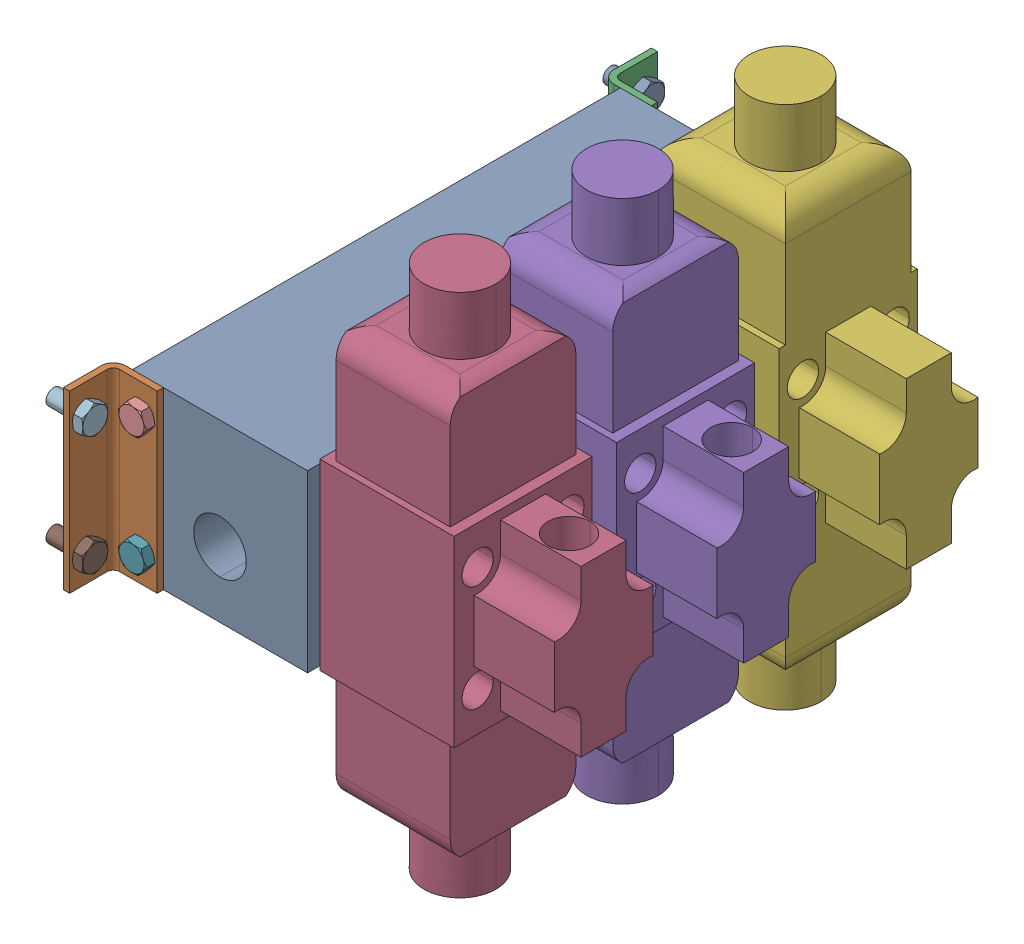
SolidWorks assembly 01-119-00-0, configuration Default. Lengths in mm.
Overall size (220.24 266.21 298.46).
14 component instances, 5 part files, 0 mates.
Components (placement in the parent):
- DAMAN-AD05S033S VALVE BLOCK-1: DAMAN-AD05S033S VALVE BLOCK [Default] at origin size (88.92 88.92 247.67)
- DAMANAD05S033S MOUNTING BRACKET-1: DAMANAD05S033S MOUNTING BRACKET [Default] at origin size (25.42 88.91 25.42)
- DAMANAD05S033S MOUNTING BRACKET-2: DAMANAD05S033S MOUNTING BRACKET [Default] at (0 88.9 -247.65) x (1 0 0) z (0 0 -1) size (25.42 88.91 25.42)
- HYVAIR-D05S-2C-12D-35 SOLENOID-1: HYVAIR-D05S-2C-12D-35 SOLENOID [Default] at origin size (108.98 266.21 70.11)
- HYVAIR-D05S-2C-12D-35 SOLENOID-2: HYVAIR-D05S-2C-12D-35 SOLENOID [Default] at (0 0 -82.5373) size (108.98 266.21 70.11)
- HYVAIR-D05S-2H-12D-35 SOLENOID-1: HYVAIR-D05S-2H-12D-35 SOLENOID [Default] at (0 0 -165.0746) size (108.98 266.21 70.11)
- .313-18 X-1: .313-18 X [Default] at (7.874 14.224 -12.7) x (0.923728 0.383049 0) z (0 0 -1) size (12.71 14.68 21.05)
- .313-18 X-2: .313-18 X [Default] at (-22.352 14.224 -265.176) x (0 0 1) z (-1 0 0) size (12.71 14.68 21.05)
- .313-18 X-3: .313-18 X [Default] at (7.874 74.676 -234.95) x (-0.923728 -0.383049 0) z (0 0 1) size (12.71 14.68 21.05)
- .313-18 X-4: .313-18 X [Default] at (7.874 74.676 -12.7) x (0.923728 0.383049 0) z (0 0 -1) size (12.71 14.68 21.05)
- .313-18 X-5: .313-18 X [Default] at (-22.352 14.224 17.526) x (0 0 1) z (-1 0 0) size (12.71 14.68 21.05)
- .313-18 X-6: .313-18 X [Default] at (-22.352 74.676 17.526) x (0 0 1) z (-1 0 0) size (12.71 14.68 21.05)
- .313-18 X-7: .313-18 X [Default] at (-22.352 74.676 -265.176) x (0 0 1) z (-1 0 0) size (12.71 14.68 21.05)
- .313-18 X-8: .313-18 X [Default] at (7.874 14.224 -234.95) x (-0.923728 -0.383049 0) z (0 0 1) size (12.71 14.68 21.05)
